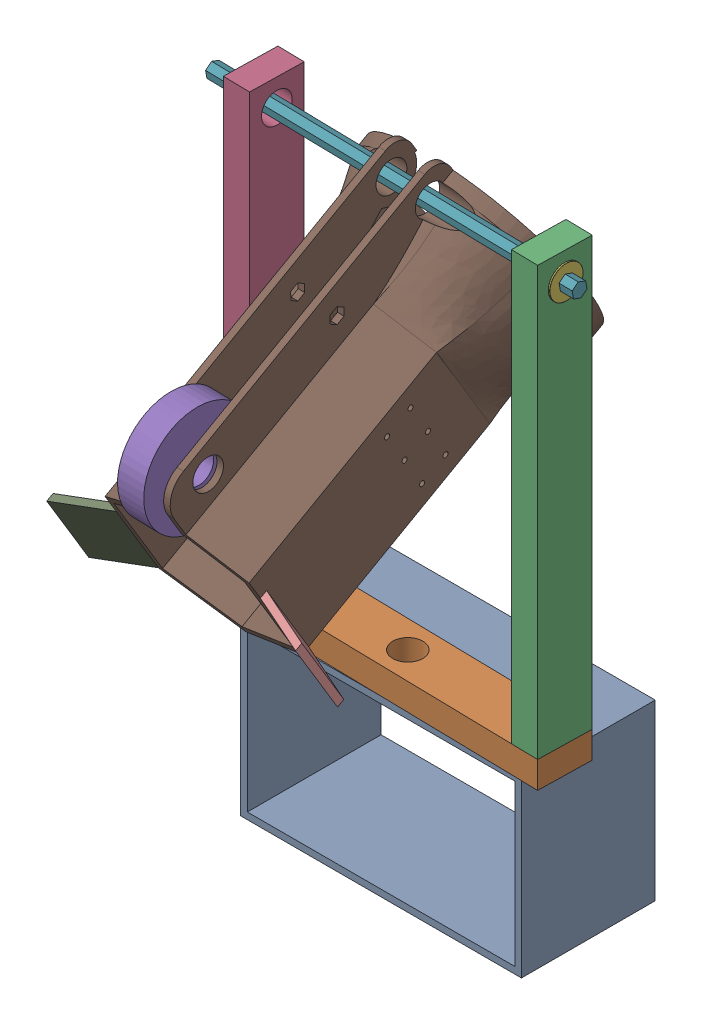
SolidWorks assembly Manip 4, configuration Default. Lengths in mm.
Overall size (355.93 604.7 399.63).
11 component instances, 8 part files, 26 mates.
Components (placement in the parent):
- elevator mount-1: elevator mount [Default] at (-339.5755 159.1291 87.8801) size (266.7 165.1 127)
- pivot bar-1: pivot bar [Default] at (-358.0654 324.2291 160.9222) x (-0.020757 0 0.999785) z (-0.999785 0 -0.020757) size (50.8 25.4 304.8)
- rotate bar-1: rotate bar [Default] at (-53.3311 349.6291 167.2488) x (-0.020757 0 0.999785) z (-0.999785 0 -0.020757) size (50.8 406.4 25.4)
- rotate bar-2: rotate bar [Default] at (-332.6709 349.6291 161.4495) x (-0.020757 0 0.999785) z (-0.999785 0 -0.020757) size (50.8 406.4 25.4)
- 3in wheel-1: 3in wheel [Default] at (-197.8267 606.78 396.7911) x (0.019179 -0.382366 -0.923812) z (-0.999785 0 -0.020757) size (101.6 101.6 25.4)
- Bearing-1: Bearing [Default] at (-60.2603 730.6291 192.5105) x (0.019505 -0.34202 -0.93949) z (0.999785 0 0.020757) size (31.12 31.12 7.93)
- Swing bar-1: Swing bar [Default] at (-39.6374 730.6291 192.9386) x (0.0159 0.642788 -0.765879) z (-0.013342 0.766044 0.642649) size (14.66 355.6 12.7)
- Bearing-2: Bearing [Default] at (-352.1907 730.6291 186.4497) x (0.0159 0.642788 -0.765879) z (-0.999785 0 -0.020757) size (31.12 31.12 7.93)
- guide-1: guide [Default] at (-330.6082 452.7488 368.0201) x (0.999785 0 0.020757) z (-0.017814 -0.513258 0.85805) size (50.8 76.2 25.4)
- guide-2: guide [Default] at (-90.1719 518.1462 412.1305) x (-0.999785 0 -0.020757) z (-0.017814 -0.513258 0.85805) size (50.8 76.2 25.4)
- Manip-withFlare-1: Manip-withFlare [Default] at (-205.8076 548.4984 169.3501) x (0.999785 0 0.020757) z (-0.017814 -0.513258 0.85805) size (205.17 222.37 304.8)
Mates (geometry in assembly coordinates):
- Coincident9: coincident anti-aligned: plane of pivot bar-1 through (-358.0654 349.6291 160.9222) normal (0 1 0); plane of rotate bar-1 through (-78.7256 349.6291 166.7216) normal (0 -1 0)
- Coincident10: coincident aligned: plane of pivot bar-1 through (-359.1199 349.6291 211.7113) normal (-0.020757 0 0.999785); plane of rotate bar-1 through (-79.7801 349.6291 217.5107) normal (-0.020757 0 0.999785)
- Coincident12: coincident anti-aligned: plane of pivot bar-1 through (-358.0654 349.6291 160.9222) normal (0 1 0); plane of rotate bar-2 through (-358.0654 349.6291 160.9222) normal (0 -1 0)
- Coincident13: coincident aligned: plane of pivot bar-1 through (-358.0654 349.6291 160.9222) normal (-0.999785 0 -0.020757); plane of rotate bar-2 through (-358.0654 349.6291 160.9222) normal (-0.999785 0 -0.020757)
- Coincident14: coincident aligned: plane of pivot bar-1 through (-359.1199 349.6291 211.7113) normal (-0.020757 0 0.999785); plane of rotate bar-2 through (-359.1199 349.6291 211.7113) normal (-0.020757 0 0.999785)
- Coincident16: coincident anti-aligned: plane of elevator mount-1 through (-339.5755 324.2291 303.7801) normal (0 1 0); plane of pivot bar-1 through (-358.0654 324.2291 160.9222) normal (0 -1 0)
- Coincident18: coincident aligned: plane of pivot bar-1 through (-53.3311 349.6291 167.2488) normal (0.999785 0 0.020757); plane of rotate bar-1 through (-53.3311 349.6291 167.2488) normal (0.999785 0 0.020757)
- Concentric5: concentric anti-aligned: cylinder of elevator mount-1 through (-206.2255 159.1281 189.4801) axis (0 1 0) radius 14.2875; cylinder of pivot bar-1 through (-206.2255 349.6291 189.4801) axis (0 -1 0) radius 14.2875
- Concentric7: concentric aligned: cylinder of rotate bar-2 through (-358.5926 730.6291 186.3168) axis (0.999785 0 0.020757) radius 14.2875; cylinder of Bearing-2 through (-360.1163 730.6291 186.2851) axis (0.999785 0 0.020757) radius 14.2875
- Coincident20: coincident anti-aligned: plane of rotate bar-2 through (-358.0654 349.6291 160.9222) normal (-0.999785 0 -0.020757); plane of Bearing-2 through (-358.3705 739.6088 175.6174) normal (0.999785 0 0.020757)
- Concentric8: concentric anti-aligned: cylinder of rotate bar-1 through (-79.2528 730.6291 192.1161) axis (0.999785 0 0.020757) radius 14.2875; cylinder of Bearing-1 through (-52.3346 730.6291 192.675) axis (-0.999785 0 -0.020757) radius 14.2875
- Coincident21: coincident anti-aligned: plane of rotate bar-1 through (-53.3311 349.6291 167.2488) normal (0.999785 0 0.020757); plane of Bearing-1 through (-53.5858 725.8511 179.5187) normal (-0.999785 0 -0.020757)
- Coincident23: coincident anti-aligned: plane of Bearing-1 through (-52.4777 733.1369 199.5637) normal (0.013342 -0.766044 -0.642649); plane of Swing bar-1 through (-395.3038 733.1369 192.4462) normal (-0.013342 0.766044 0.642649)
- Coincident24: coincident anti-aligned: plane of Bearing-1 through (-52.4512 725.9159 198.2907) normal (0.020441 0.173648 -0.984596); plane of Swing bar-1 through (-395.2774 725.9159 191.1733) normal (-0.020441 -0.173648 0.984596)
- Coincident27: coincident anti-aligned: plane of Swing bar-1 through (-395.3038 733.1369 192.4462) normal (-0.013342 0.766044 0.642649); plane of Bearing-2 through (-360.1427 737.85 187.5581) normal (0.013342 -0.766044 -0.642649)
- Distance1: distance = 12.7 mm aligned: plane of Swing bar-1 through (-39.6374 730.6291 192.9386) normal (0.999785 0 0.020757); plane of Bearing-1 through (-52.0312 725.3081 178.0589) normal (0.999785 0 0.020757)
- Concentric9: concentric aligned: cylinder of 3in wheel-1 through (-223.2213 606.78 396.2638) axis (0.999785 0 0.020757) radius 14.2875; cylinder of Manip-withFlare-1 through (-493.0381 606.78 390.6622) axis (0.999785 0 0.020757) radius 14.2875
- Width1: width anti-aligned: plane of 3in wheel-1 through (-223.2213 606.78 396.2638) normal (-0.999785 0 -0.020757); plane of Manip-withFlare-1 through (-197.8267 606.78 396.7911) normal (0.999785 0 0.020757); plane of 3in wheel-1 through (-188.7322 567.0607 417.6241) normal (0.999785 0 0.020757); plane of Manip-withFlare-1 through (-233.1726 567.0607 416.7014) normal (-0.999785 0 -0.020757)
- Coincident28: coincident anti-aligned: plane of guide-2 through (-139.8172 462.3139 355.9835) normal (-0.999785 0 -0.020757); plane of Manip-withFlare-1 through (-139.8172 462.3139 355.9835) normal (0.999785 0 0.020757)
- Coincident29: coincident aligned: line of guide-2 through (-139.8172 462.3139 355.9835) axis (-0.010653 0.858235 0.513147); line of Manip-withFlare-1 through (-139.8172 462.3139 355.9835) axis (-0.010653 0.858235 0.513147)
- Coincident30: coincident aligned: line of guide-2 through (-139.8172 462.3139 355.9835) axis (0.017814 0.513258 -0.85805); line of Manip-withFlare-1 through (-139.8172 462.3139 355.9835) axis (0.017814 0.513258 -0.85805)
- Coincident31: coincident anti-aligned: plane of guide-1 through (-280.2989 527.7114 392.1856) normal (0.999785 0 0.020757); plane of Manip-withFlare-1 through (-279.4871 462.3139 353.0838) normal (-0.999785 0 -0.020757)
- Coincident32: coincident aligned: line of guide-1 through (-280.2989 527.7114 392.1856) axis (0.010653 -0.858235 -0.513147); line of Manip-withFlare-1 through (-280.5168 545.2615 402.679) axis (0.010653 -0.858235 -0.513147)
- Coincident33: coincident aligned: line of guide-1 through (-279.4871 462.3139 353.0838) axis (0.017814 0.513258 -0.85805); line of Manip-withFlare-1 through (-279.4871 462.3139 353.0838) axis (0.017814 0.513258 -0.85805)
- Concentric10: concentric aligned: cylinder of rotate bar-1 through (-79.2528 730.6291 192.1161) axis (0.999785 0 0.020757) radius 14.2875; cylinder of Manip-withFlare-1 through (-437.9505 730.6291 184.6692) axis (0.999785 0 0.020757) radius 14.351
- Width2: width anti-aligned: plane of rotate bar-2 through (-332.6709 349.6291 161.4495) normal (0.999785 0 0.020757); plane of Manip-withFlare-1 through (-78.7256 349.6291 166.7216) normal (-0.999785 0 -0.020757); plane of rotate bar-1 through (-233.1726 567.0607 416.7014) normal (-0.999785 0 -0.020757); plane of Manip-withFlare-1 through (-188.7322 567.0607 417.6241) normal (0.999785 0 0.020757)
